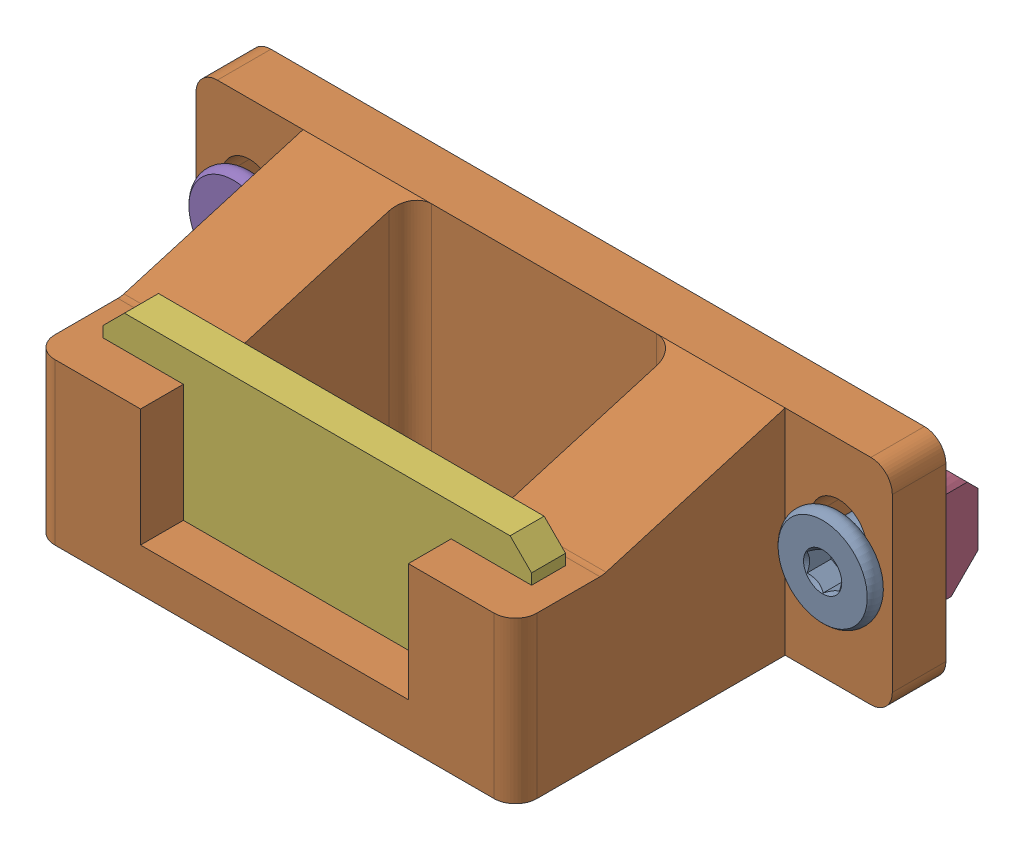
SolidWorks assembly extruder_wiper_assembly, configuration Default. Lengths in mm.
Overall size (65 20 35.18).
6 component instances, 4 part files, 0 mates.
Components (placement in the parent):
- m5_low_profile_screw_template_M5 x 10-1: m5_low_profile_screw_template_M5 x 10 [Default] at (-67.018 10 -35.175) x (0 0 -1) z (1 0 0) size (11.62 9 9)
- ooze_wiper_v1-1: ooze_wiper_v1 [Default] at (-107.018 0 -30.175) size (65 20 30.18)
- m5_locking_t_nut_20x20_generic-1: m5_locking_t_nut_20x20_generic [Default] at (-119.018 10 -35.175) x (0 -1 0) z (-1 0 0) size (10 4.5 6)
- m5_locking_t_nut_20x20_generic-2: m5_locking_t_nut_20x20_generic [Default] at (-64.018 10 -35.175) x (0 -1 0) z (-1 0 0) size (10 4.5 6)
- m5_low_profile_screw_template_M5 x 10-2: m5_low_profile_screw_template_M5 x 10 [Default] at (-122.018 10 -35.175) x (0 0 -1) z (1 0 0) size (11.62 9 9)
- silicone_wiper-1: silicone_wiper [Default] at (-114.518 3 -7.175) x (1 0 0) z (0 -1 0) size (40 3.17 15)
